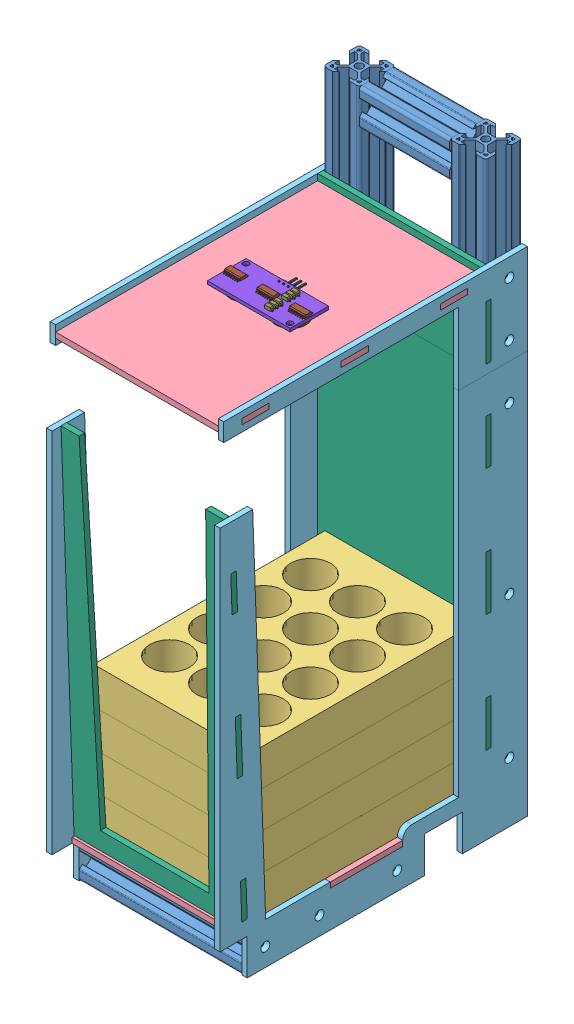
SolidWorks assembly Stack_wells, configuration Default. Lengths in mm.
Overall size (96 323 170).
33 component instances, 12 part files, 61 mates.
Components (placement in the parent):
- V-Slot 20mm x 20mm x 1000mm-2: V-Slot 20mm x 20mm x 1000mm [70] at (-4.861 37.0575 -5.6547) size (20 20 70)
- V-Slot 20mm x 20mm x 1000mm-3: V-Slot 20mm x 20mm x 1000mm [70] at (65.139 37.0575 -5.6547) size (20 20 70)
- V-Slot 20mm x 20mm x 1000mm-4: V-Slot 20mm x 20mm x 1000mm [90] at (-14.861 37.0575 4.3453) x (0 0 1) z (-1 0 0) size (20 20 90)
- ElectronicsPlatform-1: ElectronicsPlatform [Wells] at (61.739 39.3969 -75.6547) x (1 0 0) z (0 0 -1) size (63 4 76.5)
- V-Slot 20mm x 20mm x 1000mm-5: V-Slot 20mm x 20mm x 1000mm [300] at (-4.861 50.0575 -130.6547) x (1 0 0) z (0 -1 0) size (20 20 300)
- V-Slot 20mm x 20mm x 1000mm-6: V-Slot 20mm x 20mm x 1000mm [300] at (65.139 50.0575 -130.6547) x (1 0 0) z (0 -1 0) size (20 20 300)
- V-Slot 20mm x 20mm x 1000mm-7: V-Slot 20mm x 20mm x 1000mm [50] at (55.139 340.0575 -130.6547) x (0 0 -1) z (1 0 0) size (20 20 50)
- V-Slot 20mm x 20mm x 1000mm-8: V-Slot 20mm x 20mm x 1000mm [50] at (55.139 60.0575 -130.6547) x (0 0 -1) z (1 0 0) size (20 20 50)
- Wells-1: Wells [Default] at (-10.861 50.0575 10.3453) size (86 20.2 128)
- Wells-2: Wells [Default] at (-10.861 70.2575 10.3453) size (86 20.2 128)
- Wells-3: Wells [Default] at (-10.861 90.4575 10.3453) size (86 20.2 128)
- Wells-4: Wells [Default] at (-10.861 110.6575 10.3453) size (86 20.2 128)
- Top_wells-1: Top_wells [Bottom] at (-14.861 47.0575 14.3453) size (96 3 156)
- Sides_wells-1: Sides_wells [Default] at (78.139 50.0575 -117.6547) x (-1 0 0) z (0 0 -1) size (3 273 170)
- Sides_wells-2: Sides_wells [Default] at (-14.861 50.0575 -117.6547) x (-1 0 0) z (0 0 -1) size (3 273 170)
- FrontBack_wells-1: FrontBack_wells [Back] at (75.139 50.0575 -117.6547) x (0 0 -1) z (1 0 0) size (3 253 96)
- FrontBack_wells-2: FrontBack_wells [Front] at (75.139 50.2608 17.1657) x (0 0.035911 -0.999355) z (1 0 0) size (3 200 96)
- EndPieceForElectronics-1: EndPieceForElectronics [Default] at (-14.861 27.0575 -78.6547) size (90 20 3)
- Parallax Ping Sensor-1: Parallax Ping Sensor [Default] at (30.139 301.3075 -45.1547) x (0 0 -1) z (0 -1 0) size (29.3 45.7 15.59)
  - Parallax Ping PCB-1: Parallax Ping PCB [Default] at origin size (21.3 45.7 1.75)
  - Parallax Ping Transducer-1: Parallax Ping Transducer [Default] at (0 -12.69 13.25) x (1 0 0) z (0 -1 0) size (16.3 12 16.3)
  - Parallax Ping Transducer-2: Parallax Ping Transducer [Default] at (0 12.69 13.25) x (1 0 0) z (0 -1 0) size (16.3 12 16.3)
  - 3 Pin Header 90 Degree-1: 3 Pin Header 90 Degree [Default] at (11.4 0 3.25) x (0 0 1) z (0 -1 0) size (5.5 10.32 8)
  - 14 Pin SMT-1: 14 Pin SMT [Default] at (0 -17.87 -0.85) x (1 0 0) z (0 1 0) size (6 1.6 8.8)
  - 14 Pin SMT-2: 14 Pin SMT [Default] at (0 0.04 -0.85) x (1 0 0) z (0 1 0) size (6 1.6 8.8)
  - 14 Pin SMT-3: 14 Pin SMT [Default] at (0 17.95 -0.85) x (1 0 0) z (0 1 0) size (6 1.6 8.8)
  - Cap1 SMT-1: Cap1 SMT [Default] at (-2.155 7.9 -0.9689) x (0 1 0) z (-1 0 0) size (4.5 1.84 1.75)
  - Cap1 SMT-2: Cap1 SMT [Default] at (7.235 7.9 -0.9689) x (0 1 0) z (-1 0 0) size (4.5 1.84 1.75)
  - Cap1 SMT-3: Cap1 SMT [Default] at (-7.235 7.9 -0.9689) x (0 1 0) z (-1 0 0) size (4.5 1.84 1.75)
  - Cap1 SMT-4: Cap1 SMT [Default] at (4.695 7.9 -0.9689) x (0 1 0) z (-1 0 0) size (4.5 1.84 1.75)
  - Cap1 SMT-5: Cap1 SMT [Default] at (2.155 7.9 -0.9689) x (0 1 0) z (-1 0 0) size (4.5 1.84 1.75)
  - Cap1 SMT-6: Cap1 SMT [Default] at (-4.695 7.9 -0.9689) x (0 1 0) z (-1 0 0) size (4.5 1.84 1.75)
- Top_wells-2: Top_wells [Top] at (-14.861 293.5575 27.3453) size (96 3 148)
Mates (geometry in assembly coordinates):
- Coincident1: coincident aligned: plane of V-Slot 20mm x 20mm x 1000mm-2 through (0.0462 47.0575 -75.6547) normal (0 1 0); plane of V-Slot 20mm x 20mm x 1000mm-3 through (70.0462 47.0575 -75.6547) normal (0 1 0)
- Coincident2: coincident aligned: plane of V-Slot 20mm x 20mm x 1000mm-2 through (0.0462 47.0575 -75.6547) normal (0 1 0); plane of V-Slot 20mm x 20mm x 1000mm-4 through (75.139 47.0575 -0.562) normal (0 1 0)
- Coincident3: coincident aligned: plane of V-Slot 20mm x 20mm x 1000mm-2 through (-14.071 32.1503 -5.6547) normal (0 0 1); plane of V-Slot 20mm x 20mm x 1000mm-3 through (55.929 32.1503 -5.6547) normal (0 0 1)
- Coincident4: coincident anti-aligned: plane of V-Slot 20mm x 20mm x 1000mm-2 through (-14.071 32.1503 -5.6547) normal (0 0 1); plane of V-Slot 20mm x 20mm x 1000mm-4 through (75.139 41.9648 -5.6547) normal (0 0 -1)
- Coincident5: coincident aligned: plane of V-Slot 20mm x 20mm x 1000mm-2 through (-14.861 41.9648 -75.6547) normal (-1 0 0); plane of V-Slot 20mm x 20mm x 1000mm-4 through (-14.861 32.1503 -4.8647) normal (-1 0 0)
- Coincident6: coincident aligned: plane of V-Slot 20mm x 20mm x 1000mm-4 through (75.139 32.1503 -4.8647) normal (1 0 0); plane of V-Slot 20mm x 20mm x 1000mm-3 through (75.139 41.9648 -75.6547) normal (1 0 0)
- Coincident10: coincident aligned: plane of V-Slot 20mm x 20mm x 1000mm-5 through (-14.071 350.0575 -135.562) normal (0 1 0); plane of V-Slot 20mm x 20mm x 1000mm-6 through (55.929 350.0575 -135.562) normal (0 1 0)
- Coincident11: coincident aligned: plane of V-Slot 20mm x 20mm x 1000mm-5 through (-14.071 350.0575 -135.562) normal (0 1 0); plane of V-Slot 20mm x 20mm x 1000mm-7 through (5.139 350.0575 -135.562) normal (0 1 0)
- Coincident12: coincident anti-aligned: plane of V-Slot 20mm x 20mm x 1000mm-6 through (55.139 350.0575 -135.562) normal (-1 0 0); plane of V-Slot 20mm x 20mm x 1000mm-7 through (55.139 335.1503 -121.4447) normal (1 0 0)
- Coincident13: coincident anti-aligned: plane of V-Slot 20mm x 20mm x 1000mm-5 through (5.139 350.0575 -125.7475) normal (1 0 0); plane of V-Slot 20mm x 20mm x 1000mm-7 through (5.139 335.1503 -121.4447) normal (-1 0 0)
- Coincident14: coincident aligned: plane of V-Slot 20mm x 20mm x 1000mm-6 through (70.0462 350.0575 -140.6547) normal (0 0 -1); plane of V-Slot 20mm x 20mm x 1000mm-7 through (5.139 344.9648 -140.6547) normal (0 0 -1)
- Coincident15: coincident aligned: plane of V-Slot 20mm x 20mm x 1000mm-6 through (70.0462 350.0575 -140.6547) normal (0 0 -1); plane of V-Slot 20mm x 20mm x 1000mm-5 through (0.0462 350.0575 -140.6547) normal (0 0 -1)
- Coincident16: coincident aligned: plane of V-Slot 20mm x 20mm x 1000mm-5 through (0.0462 350.0575 -140.6547) normal (0 0 -1); plane of V-Slot 20mm x 20mm x 1000mm-8 through (5.139 64.9648 -140.6547) normal (0 0 -1)
- Coincident17: coincident anti-aligned: plane of V-Slot 20mm x 20mm x 1000mm-5 through (5.139 350.0575 -135.562) normal (1 0 0); plane of V-Slot 20mm x 20mm x 1000mm-8 through (5.139 55.1503 -121.4447) normal (-1 0 0)
- Coincident18: coincident aligned: plane of V-Slot 20mm x 20mm x 1000mm-5 through (-14.071 50.0575 -135.562) normal (0 -1 0); plane of V-Slot 20mm x 20mm x 1000mm-8 through (5.139 50.0575 -135.562) normal (0 -1 0)
- Coincident19: coincident aligned: plane of Wells-4 through (-10.861 130.8575 10.3453) normal (0 0 1); plane of Wells-3 through (-10.861 110.6575 10.3453) normal (0 0 1)
- Coincident20: coincident aligned: plane of Wells-4 through (-10.861 130.8575 10.3453) normal (0 0 1); plane of Wells-2 through (-10.861 90.4575 10.3453) normal (0 0 1)
- Coincident21: coincident aligned: plane of Wells-4 through (-10.861 130.8575 10.3453) normal (0 0 1); plane of Wells-1 through (-10.861 70.2575 10.3453) normal (0 0 1)
- Coincident22: coincident aligned: plane of Wells-4 through (-10.861 130.8575 10.3453) normal (-1 0 0); plane of Wells-3 through (-10.861 110.6575 10.3453) normal (-1 0 0)
- Coincident23: coincident aligned: plane of Wells-4 through (-10.861 130.8575 10.3453) normal (-1 0 0); plane of Wells-2 through (-10.861 90.4575 10.3453) normal (-1 0 0)
- Coincident24: coincident aligned: plane of Wells-4 through (-10.861 130.8575 10.3453) normal (-1 0 0); plane of Wells-1 through (-10.861 70.2575 10.3453) normal (-1 0 0)
- Coincident25: coincident anti-aligned: plane of Wells-3 through (-10.861 110.6575 10.3453) normal (0 1 0); plane of Wells-4 through (-10.861 110.6575 10.3453) normal (0 -1 0)
- Coincident26: coincident anti-aligned: plane of Wells-2 through (-10.861 90.4575 10.3453) normal (0 1 0); plane of Wells-3 through (-10.861 90.4575 10.3453) normal (0 -1 0)
- Coincident27: coincident anti-aligned: plane of Wells-1 through (-10.861 70.2575 10.3453) normal (0 1 0); plane of Wells-2 through (-10.861 70.2575 10.3453) normal (0 -1 0)
- Coincident28: coincident anti-aligned: plane of Top_wells-1 through (-14.861 47.0575 14.3453) normal (0 -1 0); plane of V-Slot 20mm x 20mm x 1000mm-3 through (60.2318 47.0575 -75.6547) normal (0 1 0)
- Coincident29: coincident anti-aligned: plane of Top_wells-1 through (-14.861 47.0575 14.3453) normal (0 -1 0); plane of V-Slot 20mm x 20mm x 1000mm-2 through (0.0462 47.0575 -75.6547) normal (0 1 0)
- Coincident30: coincident anti-aligned: plane of Sides_wells-2 through (-14.861 50.0575 -117.6547) normal (1 0 0); plane of V-Slot 20mm x 20mm x 1000mm-5 through (-14.861 350.0575 -125.7475) normal (-1 0 0)
- Coincident31: coincident anti-aligned: plane of Sides_wells-2 through (-14.861 50.0575 -117.6547) normal (1 0 0); plane of Top_wells-1 through (-14.861 50.0575 14.3453) normal (-1 0 0)
- Coincident32: coincident anti-aligned: plane of Sides_wells-2 through (-14.861 50.0575 -117.6547) normal (1 0 0); plane of V-Slot 20mm x 20mm x 1000mm-2 through (-14.861 41.9648 -75.6547) normal (-1 0 0)
- Coincident33: coincident anti-aligned: plane of Sides_wells-2 through (-14.861 50.0575 -117.6547) normal (1 0 0); plane of V-Slot 20mm x 20mm x 1000mm-4 through (-14.861 32.1503 -4.8647) normal (-1 0 0)
- Concentric1: concentric aligned: cylinder of V-Slot 20mm x 20mm x 1000mm-4 through (75.139 37.0575 4.3453) axis (-1 0 0) radius 2.1; cylinder of Sides_wells-2 through (-14.861 37.0575 4.3453) axis (-1 0 0) radius 2.5
- Coincident35: coincident anti-aligned: plane of Sides_wells-1 through (75.139 50.0575 -117.6547) normal (-1 0 0); plane of V-Slot 20mm x 20mm x 1000mm-6 through (75.139 350.0575 -135.562) normal (1 0 0)
- Coincident36: coincident anti-aligned: plane of Sides_wells-1 through (75.139 50.0575 -117.6547) normal (-1 0 0); plane of V-Slot 20mm x 20mm x 1000mm-3 through (75.139 41.9648 -75.6547) normal (1 0 0)
- Coincident39: coincident anti-aligned: plane of Sides_wells-1 through (75.139 50.0575 -117.6547) normal (-1 0 0); plane of V-Slot 20mm x 20mm x 1000mm-4 through (75.139 32.1503 -4.8647) normal (1 0 0)
- Concentric2: concentric aligned: cylinder of Sides_wells-1 through (78.139 37.0575 4.3453) axis (-1 0 0) radius 2.5; cylinder of V-Slot 20mm x 20mm x 1000mm-4 through (75.139 37.0575 4.3453) axis (-1 0 0) radius 2.1
- Coincident41: coincident aligned: plane of V-Slot 20mm x 20mm x 1000mm-5 through (-9.7682 350.0575 -140.6547) normal (0 0 -1); plane of Sides_wells-2 through (-14.861 250.0575 -140.6547) normal (0 0 -1)
- Coincident42: coincident aligned: plane of V-Slot 20mm x 20mm x 1000mm-6 through (70.0462 350.0575 -140.6547) normal (0 0 -1); plane of Sides_wells-1 through (78.139 250.0575 -140.6547) normal (0 0 -1)
- Coincident44: coincident aligned: plane of V-Slot 20mm x 20mm x 1000mm-2 through (-9.7682 27.0575 -75.6547) normal (0 -1 0); plane of Sides_wells-2 through (-14.861 27.0575 -140.6547) normal (0 -1 0)
- Coincident45: coincident anti-aligned: plane of V-Slot 20mm x 20mm x 1000mm-5 through (0.0462 350.0575 -120.6547) normal (0 0 1); plane of FrontBack_wells-1 through (75.139 50.0575 -120.6547) normal (0 0 -1)
- Coincident46: coincident anti-aligned: plane of Sides_wells-2 through (-14.861 50.0575 -117.6547) normal (1 0 0); plane of FrontBack_wells-1 through (-14.861 50.0575 -120.6547) normal (-1 0 0)
- Coincident47: coincident anti-aligned: plane of Sides_wells-2 through (-14.861 50.0575 -117.6547) normal (1 0 0); plane of FrontBack_wells-2 through (-14.861 50.3685 14.1677) normal (-1 0 0)
- Coincident48: coincident anti-aligned: plane of Sides_wells-2 through (-14.861 55.2575 17.3453) normal (0 0.035911 -0.999355); plane of FrontBack_wells-2 through (75.139 50.2608 17.1657) normal (0 -0.035911 0.999355)
- Coincident49: coincident anti-aligned: plane of Top_wells-1 through (-14.861 50.0575 -117.6547) normal (0 0 -1); plane of FrontBack_wells-1 through (75.139 50.0575 -117.6547) normal (0 0 1)
- Coincident50: coincident anti-aligned: plane of Sides_wells-2 through (-14.861 55.2575 17.3453) normal (0 0.999355 0.035911); plane of FrontBack_wells-2 through (-14.861 55.2575 17.3453) normal (0 -0.999355 -0.035911)
- Coincident51: coincident anti-aligned: plane of Wells-1 through (-10.861 50.0575 10.3453) normal (0 -1 0); plane of Top_wells-1 through (-14.861 50.0575 14.3453) normal (0 1 0)
- Coincident52: coincident anti-aligned: plane of Wells-1 through (-10.861 70.2575 -117.6547) normal (0 0 -1); plane of FrontBack_wells-1 through (75.139 50.0575 -117.6547) normal (0 0 1)
- Coincident54: coincident anti-aligned: plane of V-Slot 20mm x 20mm x 1000mm-2 through (-14.071 32.1503 -75.6547) normal (0 0 -1); plane of EndPieceForElectronics-1 through (-14.861 27.0575 -75.6547) normal (0 0 1)
- Concentric3: concentric anti-aligned: cylinder of V-Slot 20mm x 20mm x 1000mm-2 through (-4.861 37.0575 -75.6547) axis (0 0 1) radius 2.1; cylinder of EndPieceForElectronics-1 through (-4.861 37.0575 -75.6547) axis (0 0 -1) radius 2.5
- Concentric5: concentric anti-aligned: cylinder of V-Slot 20mm x 20mm x 1000mm-3 through (65.139 37.0575 -75.6547) axis (0 0 1) radius 2.1; cylinder of EndPieceForElectronics-1 through (65.139 37.0575 -75.6547) axis (0 0 -1) radius 2.5
- Coincident55: coincident anti-aligned: plane of ElectronicsPlatform-1 through (-1.261 35.3969 -75.6547) normal (0 0 -1); plane of EndPieceForElectronics-1 through (-14.861 27.0575 -75.6547) normal (0 0 1)
- Coincident56: coincident anti-aligned: plane of Top_wells-1 through (-14.861 50.0575 14.3453) normal (0 1 0); plane of FrontBack_wells-1 through (75.139 50.0575 -120.6547) normal (0 -1 0)
- Coincident57: coincident anti-aligned: plane of Wells-1 through (75.139 70.2575 10.3453) normal (1 0 0); plane of Sides_wells-1 through (75.139 50.0575 -117.6547) normal (-1 0 0)
- Coincident58: coincident aligned: line of V-Slot 20mm x 20mm x 1000mm-3 through (61.739 39.3969 -75.6547) axis (0 0 1); line of ElectronicsPlatform-1 through (61.739 39.3969 -75.6547) axis (0 0 1)
- Parallel2: parallel aligned: plane of ElectronicsPlatform-1 through (61.739 35.3969 -75.6547) normal (0 -1 0); plane of Top_wells-1 through (-14.861 47.0575 14.3453) normal (0 -1 0)
- Coincident59: coincident anti-aligned: plane of V-Slot 20mm x 20mm x 1000mm-8 through (5.139 50.0575 -135.562) normal (0 -1 0); plane of Top_wells-1 through (-14.861 50.0575 14.3453) normal (0 1 0)
- Coincident60: coincident anti-aligned: plane of FrontBack_wells-1 through (75.139 50.0575 -117.6547) normal (0 0 1); plane of Top_wells-2 through (-14.861 293.5575 -117.6547) normal (0 0 -1)
- Coincident61: coincident anti-aligned: plane of Sides_wells-2 through (-14.861 50.0575 -117.6547) normal (1 0 0); plane of Top_wells-2 through (-14.861 296.5575 27.3453) normal (-1 0 0)
- Coincident62: coincident anti-aligned: plane of FrontBack_wells-1 through (50.139 293.5575 -117.6547) normal (0 1 0); plane of Top_wells-2 through (-14.861 293.5575 27.3453) normal (0 -1 0)
- Concentric6: concentric anti-aligned: cylinder of Parallax Ping Sensor-1/Parallax Ping Transducer-1 through (17.449 288.0575 -45.1547) axis (0 -1 0) radius 8.15; cylinder of Top_wells-2 through (17.449 293.5575 -45.1547) axis (0 1 0) radius 8.15
- Concentric7: concentric anti-aligned: cylinder of Parallax Ping Sensor-1/Parallax Ping Transducer-2 through (42.829 288.0575 -45.1547) axis (0 -1 0) radius 8.15; cylinder of Top_wells-2 through (42.829 293.5575 -45.1547) axis (0 1 0) radius 8.15
- Coincident63: coincident anti-aligned: plane of Parallax Ping Sensor-1/3 Pin Header 90 Degree-1 through (26.139 296.5575 -55.3047) normal (0 -1 0); plane of Top_wells-2 through (-14.861 296.5575 27.3453) normal (0 1 0)
